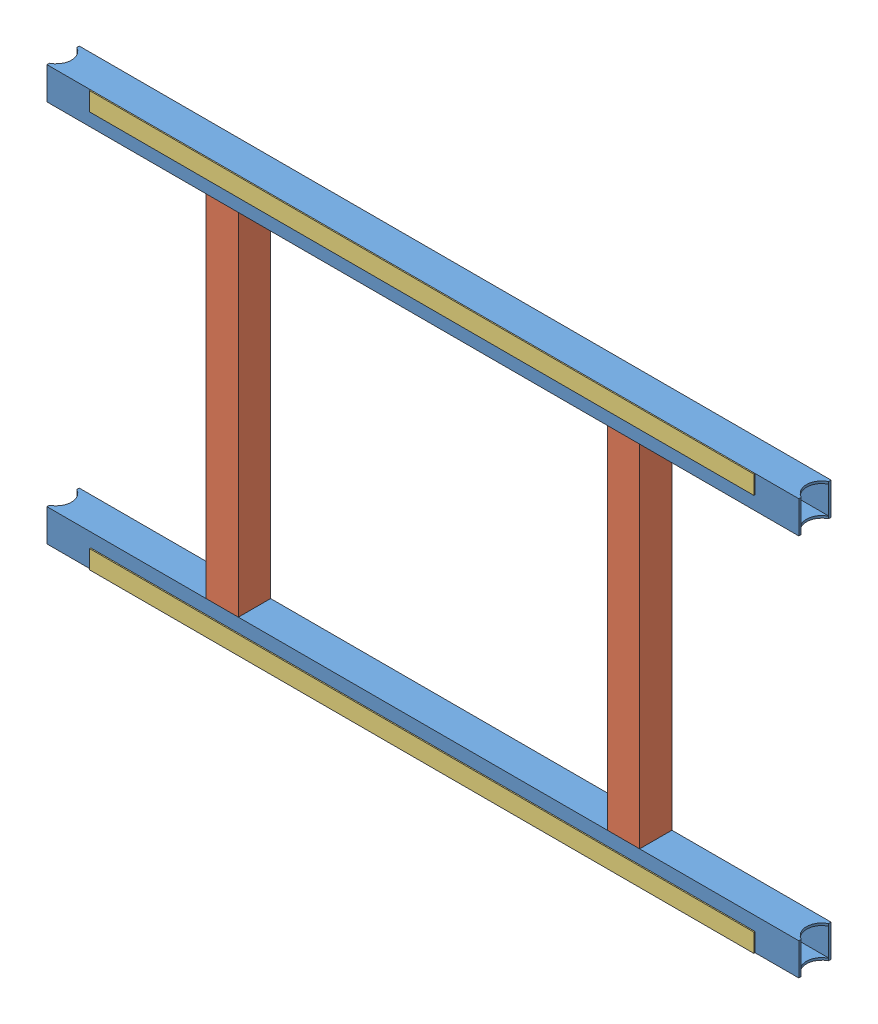
SolidWorks assembly GE-22343, configuration Default. Lengths in mm.
Overall size (1087.37 571.5 46.04).
11 component instances, 4 part files, 6 mates.
Components (placement in the parent):
- GE-22342-1: GE-22342 [Default] at origin size (1087.37 571.5 44.45)
  - GE-22342-01-1: GE-22342-01 [Default] at (0 0 -22.225) size (1026.16 44.45 44.45)
  - GE-22342-01-2: GE-22342-01 [Default] at (0 527.05 -22.225) size (1026.16 44.45 44.45)
  - GE-22342-03-1: GE-22342-03 [Default] at (-522.605 434.975 -22.225) size (42.16 136.53 42.16)
  - GE-22342-03-2: GE-22342-03 [Default] at (-522.605 0 -22.225) size (42.16 136.53 42.16)
  - GE-22342-03-3: GE-22342-03 [Default] at (522.605 434.975 -22.225) size (42.16 136.53 42.16)
  - GE-22342-03-4: GE-22342-03 [Default] at (522.605 0 -22.225) size (42.16 136.53 42.16)
  - GE-22342-02-1: GE-22342-02 [Default] at (-298.45 44.45 0) size (44.45 482.6 44.45)
  - GE-22342-02-2: GE-22342-02 [Default] at (254 44.45 0) size (44.45 482.6 44.45)
- Hook_1_36-1: Hook_1_36 [Default] at (-457.2 571.5 1.5875) x (1 0 0) z (0 1 0) size (914.4 1.59 25.4)
- Hook_1_36-2: Hook_1_36 [Default] at (-457.2 25.4 1.5875) x (1 0 0) z (0 1 0) size (914.4 1.59 25.4)
Mates (geometry in assembly coordinates):
- Coincident1: coincident anti-aligned: plane of fenderFrame_mockV2-1/fenderHorizontal_mockV2-2 through (0 571.5 0) normal (0 0 1); plane of Hook_1_36-1 through (-457.2 571.5 0) normal (0 0 -1)
- Coincident2: coincident aligned: plane of fenderFrame_mockV2-1/fenderHorizontal_mockV2-2 through (0 571.5 -22.225) normal (0 1 0); plane of Hook_1_36-1 through (-457.2 571.5 0) normal (0 1 0)
- Width1: width aligned: plane of fenderFrame_mockV2-1/fenderHorizontal_mockV2-2 through (513.08 571.5 -22.225) normal (1 0 0); plane of Hook_1_36-1 through (-513.08 571.5 -22.225) normal (-1 0 0); plane of fenderFrame_mockV2-1/fenderHorizontal_mockV2-2 through (457.2 571.5 0) normal (1 0 0); plane of Hook_1_36-1 through (-457.2 571.5 0) normal (-1 0 0)
- Coincident3: coincident anti-aligned: plane of fenderFrame_mockV2-1/fenderHorizontal_mockV2-1 through (0 44.45 0) normal (0 0 1); plane of Hook_1_36-2 through (-457.2 25.4 0) normal (0 0 -1)
- Coincident4: coincident aligned: plane of fenderFrame_mockV2-1/fenderHorizontal_mockV2-1 through (0 0 -22.225) normal (0 -1 0); plane of Hook_1_36-2 through (-457.2 0 0) normal (0 -1 0)
- Coincident5: coincident aligned: plane of Hook_1_36-1 through (-457.2 571.5 0) normal (-1 0 0); plane of Hook_1_36-2 through (-457.2 25.4 0) normal (-1 0 0)
